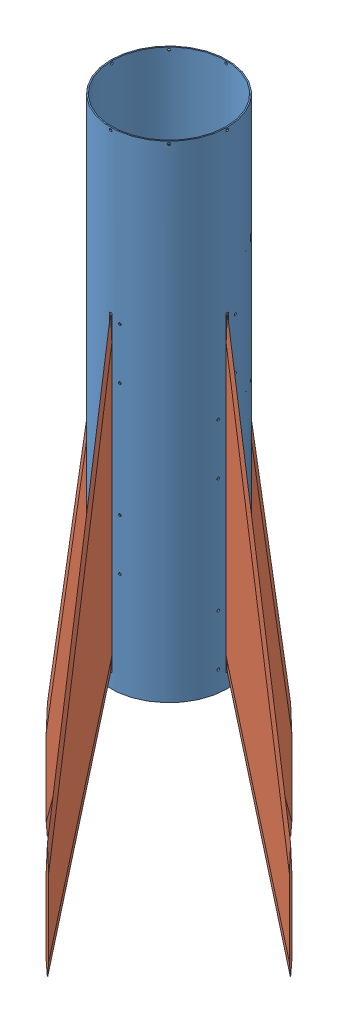
SolidWorks assembly 10002-R03_FIN_ASSEMBLY, configuration Default. Lengths in mm.
Overall size (635 1841.5 635).
21 component instances, 3 part files, 19 mates.
Components (placement in the parent):
- 14024_R01_AIRFRAME_SEC4-1: 14024_R01_AIRFRAME_SEC4 [Default] x (1 0 0) z (0 1 0) size (304.8 304.8 1270)
- 14010-R06_FIN-15: 14010-R06_FIN [Default] at (3.175 38.1 -152.4) x (0 -1 0) z (-1 0 0) size (1422.4 206.38 6.35)
- 14013-R04_FIN_L_BRACKET-41: 14013-R04_FIN_L_BRACKET [Default] at (0.127 850.9 0) x (-1 0 0) z (0 0 1) size (34.74 165.82 38.06)
- 14013-R04_FIN_L_BRACKET-43: 14013-R04_FIN_L_BRACKET [Default] at (-0.127 38.1 0) size (34.74 165.82 38.06)
- 14013-R04_FIN_L_BRACKET-44: 14013-R04_FIN_L_BRACKET [Default] at (-0.127 469.9 0) size (34.74 165.82 38.06)
- 14013-R04_FIN_L_BRACKET-45: 14013-R04_FIN_L_BRACKET [Default] at (0.127 419.1 0) x (-1 0 0) z (0 0 1) size (34.74 165.82 38.06)
- 14013-R04_FIN_L_BRACKET-46: 14013-R04_FIN_L_BRACKET [Default] at (0 419.1 -0.127) x (0 0 1) z (1 0 0) size (34.74 165.82 38.06)
- 14013-R04_FIN_L_BRACKET-47: 14013-R04_FIN_L_BRACKET [Default] at (-0.127 419.1 0) x (1 0 0) z (0 0 -1) size (34.74 165.82 38.06)
- 14013-R04_FIN_L_BRACKET-48: 14013-R04_FIN_L_BRACKET [Default] at (0 419.1 0.127) x (0 0 -1) z (-1 0 0) size (34.74 165.82 38.06)
- 14013-R04_FIN_L_BRACKET-49: 14013-R04_FIN_L_BRACKET [Default] at (0 469.9 0.127) x (0 0 -1) z (1 0 0) size (34.74 165.82 38.06)
- 14013-R04_FIN_L_BRACKET-50: 14013-R04_FIN_L_BRACKET [Default] at (0.127 469.9 0) x (-1 0 0) z (0 0 -1) size (34.74 165.82 38.06)
- 14013-R04_FIN_L_BRACKET-51: 14013-R04_FIN_L_BRACKET [Default] at (0 469.9 -0.127) x (0 0 1) z (-1 0 0) size (34.74 165.82 38.06)
- 14013-R04_FIN_L_BRACKET-52: 14013-R04_FIN_L_BRACKET [Default] at (0 38.1 0.127) x (0 0 -1) z (1 0 0) size (34.74 165.82 38.06)
- 14013-R04_FIN_L_BRACKET-53: 14013-R04_FIN_L_BRACKET [Default] at (0.127 38.1 0) x (-1 0 0) z (0 0 -1) size (34.74 165.82 38.06)
- 14013-R04_FIN_L_BRACKET-54: 14013-R04_FIN_L_BRACKET [Default] at (0 38.1 -0.127) x (0 0 1) z (-1 0 0) size (34.74 165.82 38.06)
- 14013-R04_FIN_L_BRACKET-55: 14013-R04_FIN_L_BRACKET [Default] at (0 850.9 -0.127) x (0 0 1) z (1 0 0) size (34.74 165.82 38.06)
- 14013-R04_FIN_L_BRACKET-56: 14013-R04_FIN_L_BRACKET [Default] at (-0.127 850.9 0) x (1 0 0) z (0 0 -1) size (34.74 165.82 38.06)
- 14013-R04_FIN_L_BRACKET-57: 14013-R04_FIN_L_BRACKET [Default] at (0 850.9 0.127) x (0 0 -1) z (-1 0 0) size (34.74 165.82 38.06)
- 14010-R06_FIN-16: 14010-R06_FIN [Default] at (-152.4 38.1 -3.175) x (0 -1 0) z (0 0 1) size (1422.4 206.38 6.35)
- 14010-R06_FIN-17: 14010-R06_FIN [Default] at (-3.175 38.1 152.4) x (0 -1 0) z (1 0 0) size (1422.4 206.38 6.35)
- 14010-R06_FIN-18: 14010-R06_FIN [Default] at (152.4 38.1 3.175) x (0 -1 0) z (0 0 -1) size (1422.4 206.38 6.35)
Mates (geometry in assembly coordinates):
- Coincident22: coincident: plane of 14024_R01_AIRFRAME_SEC4-1 through (0 0 0) normal (0 0 -1); plane of assembly through (0 0 0) normal (0 0 1)
- Coincident23: coincident: plane of 14024_R01_AIRFRAME_SEC4-1 through (0 0 0) normal (0 1 0); plane of assembly through (0 0 0) normal (0 1 0)
- Coincident24: coincident: plane of 14024_R01_AIRFRAME_SEC4-1 through (0 0 0) normal (1 0 0); plane of assembly through (0 0 0) normal (1 0 0)
- Coincident30: coincident: plane of 14024_R01_AIRFRAME_SEC4-1 through (152.4 850.9 3.175) normal (0 -1 0); plane of 14010-R06_FIN-15 through (3.175 850.9 -149.225) normal (0 1 0)
- Tangent4: tangent: cylinder of 14024_R01_AIRFRAME_SEC4-1 through (0 1270 0) axis (0 -1 0) radius 152.4; plane of 14010-R06_FIN-15 through (3.175 38.1 -152.4) normal (0 0 -1)
- Concentric1: concentric: cylinder of 14010-R06_FIN-15 through (-3.176 835.025 -127) axis (1 0 0) radius 3.175; cylinder of 14013-R04_FIN_L_BRACKET-41 through (-37.9185 835.025 -127) axis (1 0 0) radius 3.175
- Concentric2: concentric: cylinder of 14010-R06_FIN-15 through (-3.176 701.675 -127) axis (1 0 0) radius 3.175; cylinder of 14013-R04_FIN_L_BRACKET-41 through (-37.9185 701.675 -127) axis (1 0 0) radius 3.175
- Concentric4: concentric: cylinder of 14010-R06_FIN-15 through (-3.176 269.875 -127) axis (1 0 0) radius 3.175; cylinder of 14013-R04_FIN_L_BRACKET-45 through (-37.9185 269.875 -127) axis (1 0 0) radius 3.175
- Concentric5: concentric: cylinder of 14010-R06_FIN-15 through (-3.176 403.225 -127) axis (1 0 0) radius 3.175; cylinder of 14013-R04_FIN_L_BRACKET-45 through (-37.9185 403.225 -127) axis (1 0 0) radius 3.175
- Concentric8: concentric: cylinder of 14010-R06_FIN-15 through (-3.176 619.125 -127) axis (1 0 0) radius 3.175; cylinder of 14013-R04_FIN_L_BRACKET-44 through (37.9185 619.125 -127) axis (-1 0 0) radius 3.175
- Concentric9: concentric: cylinder of 14010-R06_FIN-15 through (-3.176 485.775 -127) axis (1 0 0) radius 3.175; cylinder of 14013-R04_FIN_L_BRACKET-44 through (37.9185 485.775 -127) axis (-1 0 0) radius 3.175
- Concentric12: concentric: cylinder of 14010-R06_FIN-15 through (-3.176 53.975 -127) axis (1 0 0) radius 3.175; cylinder of 14013-R04_FIN_L_BRACKET-43 through (37.9185 53.975 -127) axis (-1 0 0) radius 3.175
- Concentric14: concentric: cylinder of 14010-R06_FIN-15 through (-3.176 187.325 -127) axis (1 0 0) radius 3.175; cylinder of 14013-R04_FIN_L_BRACKET-43 through (37.9185 187.325 -127) axis (-1 0 0) radius 3.175
- Parallel3: parallel: plane of 14024_R01_AIRFRAME_SEC4-1 through (0 1270 0) normal (0 1 0); plane of 14010-R06_FIN-15 through (3.175 850.9 -149.225) normal (0 1 0)
- Coincident40: coincident: plane of 14024_R01_AIRFRAME_SEC4-1 through (3.175 850.9 -152.4) normal (-1 0 0); plane of 14010-R06_FIN-15 through (3.175 38.1 -152.4) normal (1 0 0)
- Coincident41: coincident: plane of 14010-R06_FIN-15 through (-3.175 38.1 -152.4) normal (-1 0 0); plane of 14013-R04_FIN_L_BRACKET-41 through (-3.175 685.8 0) normal (1 0 0)
- Coincident42: coincident: plane of 14010-R06_FIN-15 through (3.175 38.1 -152.4) normal (1 0 0); plane of 14013-R04_FIN_L_BRACKET-44 through (3.175 635 0) normal (-1 0 0)
- Coincident44: coincident: plane of 14010-R06_FIN-15 through (-3.175 38.1 -152.4) normal (-1 0 0); plane of 14013-R04_FIN_L_BRACKET-45 through (-3.175 254 0) normal (1 0 0)
- Coincident45: coincident: plane of 14010-R06_FIN-15 through (3.175 38.1 -152.4) normal (1 0 0); plane of 14013-R04_FIN_L_BRACKET-43 through (3.175 203.2 0) normal (-1 0 0); plane of ?
